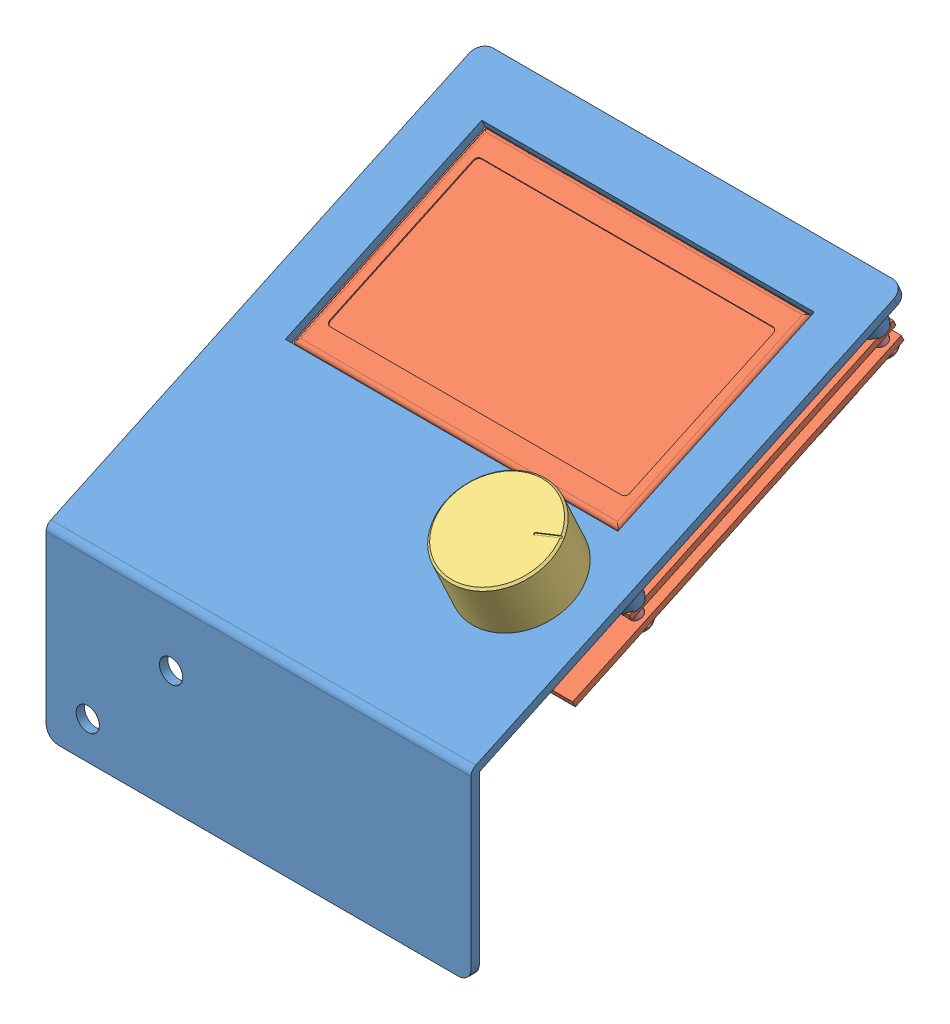
SolidWorks assembly ASM Display, configuration Standard. Lengths in mm.
Overall size (102 101.36 115.85).
9 component instances, 5 part files, 20 mates.
Components (placement in the parent):
- LCD support-1: LCD support [Standard] x (0 1 0) z (1 0 0) size (92.88 105.44 102)
- lcd-1: lcd [Standard] at (52 59.8623 -67.9755) x (1 0 0) z (0 0.906308 0.422618) size (93 87 45.5)
- lcd Knob-1: lcd Knob [Standard] at (83.1 60.6587 -30.6409) x (0.377599 -0.391331 0.839213) z (-0.925969 -0.15958 0.342221) size (25 13 25)
- M5X8Pan Head Screw-1: M5X8Pan Head Screw [Standard] at (10 9 2.75) x (0 0 -1) z (-0.831867 -0.554975 0) (suppressed, hidden)
- M5X8Pan Head Screw-2: M5X8Pan Head Screw [Standard] at (30 29 2.75) x (0 0 -1) z (-0.776515 -0.630099 0) (suppressed, hidden)
- M3X8 Pan Head Screw-1: M3X8 Pan Head Screw [Standard] at (95.95 75.6731 -105.7861) x (0 0.906308 0.422618) z (0.769965 0.269667 -0.578302) size (10.25 6.02 6.02)
- M3X8 Pan Head Screw-2: M3X8 Pan Head Screw [Standard] at (8.05 75.6731 -105.7861) x (0 0.906308 0.422618) z (0.597316 0.338942 -0.726864) size (10.25 6.02 6.02)
- M3X8 Pan Head Screw-3: M3X8 Pan Head Screw [Standard] at (8.05 48.2452 -46.9667) x (0 0.906308 0.422618) z (0.382581 0.390466 -0.837358) size (10.25 6.02 6.02)
- M3X8 Pan Head Screw-4: M3X8 Pan Head Screw [Standard] at (95.95 48.2452 -46.9667) x (0 0.906308 0.422618) z (0.145972 0.418091 -0.8966) size (10.25 6.02 6.02)
Mates (geometry in assembly coordinates):
- Deckungsgleich16: coincident aligned: plane of LCD support-1 through (0 36.3665 16.958) normal (0 0.906308 0.422618); plane of lcd-1 through (52 73.0944 -61.8052) normal (0 0.906308 0.422618)
- Konzentrisch7: concentric aligned: cylinder of LCD support-1 through (83.1 49.8736 -35.6701) axis (0 0.906308 0.422618) radius 5; cylinder of lcd-1 through (83.1 47.0641 -36.9802) axis (0 0.906308 0.422618) radius 3
- Parallel2: parallel aligned: plane of LCD support-1 through (102 44.8126 -1.1548) normal (1 0 0); plane of lcd-1 through (98.5 41.4784 -28.5511) normal (1 0 0)
- Deckungsgleich39: coincident anti-aligned: plane of LCD support-1 through (102 0 0) normal (0 0 1); plane of M5X8Pan Head Screw-1 through (10 9 0) normal (0 0 -1)
- Deckungsgleich40: coincident anti-aligned: plane of LCD support-1 through (102 0 0) normal (0 0 1); plane of M5X8Pan Head Screw-2 through (30 29 0) normal (0 0 -1)
- Konzentrisch8: concentric aligned: cylinder of lcd-1 through (83.1 47.0641 -36.9802) axis (0 0.906308 0.422618) radius 3; cylinder of lcd Knob-1 through (83.1 72.4407 -25.1469) axis (0 0.906308 0.422618) radius 2.5
- Deckungsgleich17: coincident anti-aligned: plane of lcd-1 through (52 82.9731 -57.1987) normal (0 0.906308 0.422618); plane of lcd Knob-1 through (83.1 68.8154 -26.8374) normal (0 -0.906308 -0.422618)
- Konzentrisch54: concentric anti-aligned: cylinder of lcd-1 through (95.95 82.6064 -102.5531) axis (0 0.906308 0.422618) radius 1.55; cylinder of M3X8 Pan Head Screw-1 through (95.95 82.6064 -102.5531) axis (0 -0.906308 -0.422618) radius 1.5
- Deckungsgleich77: coincident anti-aligned: plane of lcd-1 through (52 59.8623 -67.9755) normal (0 -0.906308 -0.422618); plane of M3X8 Pan Head Screw-1 through (95.95 77.1685 -105.0888) normal (0 0.906308 0.422618)
- Konzentrisch66: concentric anti-aligned: cylinder of lcd-1 through (8.05 82.6064 -102.5531) axis (0 0.906308 0.422618) radius 1.55; cylinder of M3X8 Pan Head Screw-2 through (8.05 82.6064 -102.5531) axis (0 -0.906308 -0.422618) radius 1.5
- Deckungsgleich78: coincident anti-aligned: plane of lcd-1 through (52 59.8623 -67.9755) normal (0 -0.906308 -0.422618); plane of M3X8 Pan Head Screw-2 through (8.05 77.1685 -105.0888) normal (0 0.906308 0.422618)
- Konzentrisch67: concentric anti-aligned: cylinder of lcd-1 through (8.05 55.1784 -43.7337) axis (0 0.906308 0.422618) radius 1.55; cylinder of M3X8 Pan Head Screw-3 through (8.05 55.1784 -43.7337) axis (0 -0.906308 -0.422618) radius 1.5
- Deckungsgleich79: coincident anti-aligned: plane of lcd-1 through (52 59.8623 -67.9755) normal (0 -0.906308 -0.422618); plane of M3X8 Pan Head Screw-3 through (8.05 49.7406 -46.2694) normal (0 0.906308 0.422618)
- Konzentrisch68: concentric anti-aligned: cylinder of lcd-1 through (95.95 55.1784 -43.7337) axis (0 0.906308 0.422618) radius 1.55; cylinder of M3X8 Pan Head Screw-4 through (95.95 55.1784 -43.7337) axis (0 -0.906308 -0.422618) radius 1.5
- Deckungsgleich80: coincident anti-aligned: plane of lcd-1 through (52 59.8623 -67.9755) normal (0 -0.906308 -0.422618); plane of M3X8 Pan Head Screw-4 through (95.95 49.7406 -46.2694) normal (0 0.906308 0.422618)
- Konzentrisch69: concentric aligned: cylinder of LCD support-1 through (30 29 -8.5) axis (0 0 1) radius 2.8; cylinder of M5X8Pan Head Screw-2 through (30 29 -10) axis (0 0 1) radius 2.5
- Konzentrisch70: concentric aligned: cylinder of LCD support-1 through (10 9 -8.5) axis (0 0 1) radius 2.8; cylinder of M5X8Pan Head Screw-1 through (10 9 -10) axis (0 0 1) radius 2.5
- Deckungsgleich81: coincident aligned: plane of LCD support-1 through (0 0 0) normal (0 0 1); plane of assembly through (0 0 0) normal (0 0 1)
- Deckungsgleich82: coincident aligned: plane of LCD support-1 through (0 0 0) normal (1 0 0); plane of assembly through (0 0 0) normal (1 0 0)
- Deckungsgleich83: coincident aligned: plane of LCD support-1 through (0 0 0) normal (0 1 0); plane of assembly through (0 0 0) normal (0 1 0)
